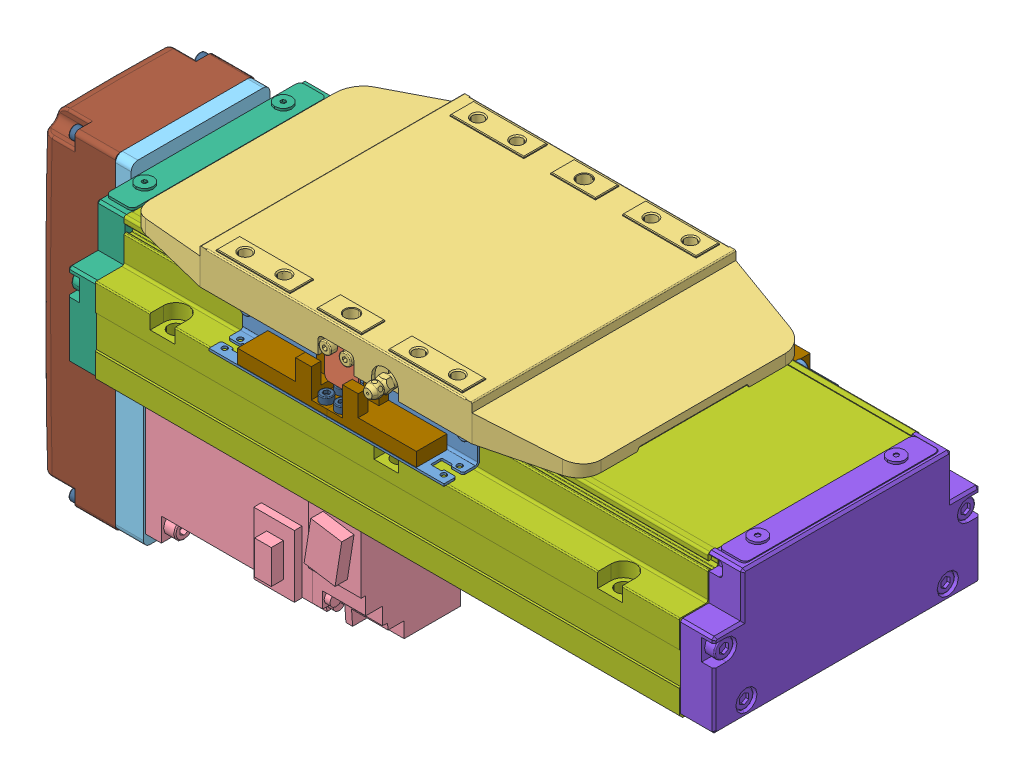
SolidWorks assembly G12-BM-400W, configuration Default. Lengths in mm.
Overall size (330.51 158.5 133.6).
25 component instances, 11 part files, 62 mates.
Components (placement in the parent):
- 304开关座片G5-12^G12-BM-400W-1: 304开关座片G5-12^G12-BM-400W [Default] at (209 38.5 -47.2) x (-1 0 0) z (0 0 -1) size (52.5 15.7 21) (virtual)
- 304开关座片G5-12^G12-BM-400W-2: 304开关座片G5-12^G12-BM-400W [Default] at (54 38.5 47.2) size (52.5 15.7 21) (virtual)
- 304开关座片G5-12^G12-BM-400W-3: 304开关座片G5-12^G12-BM-400W [Default] at (106.5 38.5 47.2) size (52.5 15.7 21) (virtual)
- 304感应片G8-12^G12-BM-400W-1: 304感应片G8-12^G12-BM-400W [Default] at (106.5 56.7 0) x (1 0 0) z (0 0 -1) size (15 17 1) (virtual)
- 304感应片G8-12^G12-BM-400W-2: 304感应片G8-12^G12-BM-400W [Default] at (106.5 56.7 0) x (-1 0 0) z (0 0 1) size (15 17 1) (virtual)
- 滑台G12^G12-BM-400W-1: 滑台G12^G12-BM-400W [Default] at (106.5 59.3 0) size (201.5 16.7 133.6) (virtual)
- 三菱400W^G12-BM-400W-1: 三菱400W^G12-BM-400W [Default] at (-7.5 -47.5 0) x (0 0 1) z (0 1 0) size (68.8 128.3 60) (virtual)
- 电机板G12-BLR-P60^G12-BM-400W-1: 电机板G12-BLR-P60^G12-BM-400W [Default] at origin size (12.5 146 62) (virtual)
- 丝杆座板G12^G12-BM-400W-1: 丝杆座板G12^G12-BM-400W [Default] at origin size (20.5 58.7 119) (virtual)
- 复件 复件 底座GY12+211^G12-BM-400W-1: 复件 复件 底座GY12+211^G12-BM-400W [默认] x (0 0 -1) z (1 0 0) size (120 58 261) (virtual)
- 塑胶轴承座G12^G12-BM-400W-4: 塑胶轴承座G12^G12-BM-400W [Default] at (261 0 0) size (15 58.9 119) (virtual)
- 复件 复件 光电开关EE-SX674^G12-BM-400W-1: 复件 复件 光电开关EE-SX674^G12-BM-400W [默认] at (66.5 41.8 49.4) size (40 15.5 13.6) (virtual)
- 复件 复件 光电开关EE-SX674^G12-BM-400W-2: 复件 复件 光电开关EE-SX674^G12-BM-400W [默认] at (146.5 41.8 63) x (-1 0 0) z (0 0 -1) size (40 15.5 13.6) (virtual)
- 复件 复件 光电开关EE-SX674^G12-BM-400W-3: 复件 复件 光电开关EE-SX674^G12-BM-400W [默认] at (196.5 41.8 -49.4) x (-1 0 0) z (0 0 -1) size (40 15.5 13.6) (virtual)
- hexagon socket head cap screws gb-5: hexagon socket head cap screws gb [GB_FASTENER_SCREWS_HSHCS M3X5-N] at (103 47.4 52.7) x (0 -1 0) z (0 0 1) size (8 5.5 5.5)
- hexagon socket head cap screws gb-6: hexagon socket head cap screws gb [GB_FASTENER_SCREWS_HSHCS M3X5-N] at (103 47.4 59.7) x (0 -1 0) z (0.994193 0 0.107614) size (8 5.5 5.5)
- hexagon socket head cap screws gb-7: hexagon socket head cap screws gb [GB_FASTENER_SCREWS_HSHCS M3X5-N] at (110 47.4 59.7) x (0 -1 0) z (0.983929 0 -0.178562) size (8 5.5 5.5)
- hexagon socket head cap screws gb-8: hexagon socket head cap screws gb [GB_FASTENER_SCREWS_HSHCS M3X5-N] at (110 47.4 52.7) x (0 -1 0) z (0 0 1) size (8 5.5 5.5)
- hexagon socket head cap screws gb-9: hexagon socket head cap screws gb [GB_FASTENER_SCREWS_HSHCS M3X20-N] at (-41.2 60.5 -28) size (23 5.5 5.5)
- hexagon socket head cap screws gb-10: hexagon socket head cap screws gb [GB_FASTENER_SCREWS_HSHCS M3X20-N] at (-41.2 60.5 28) x (1 0 0) z (0 -0.477409 0.878681) size (23 5.5 5.5)
- hexagon socket head cap screws gb-11: hexagon socket head cap screws gb [GB_FASTENER_SCREWS_HSHCS M3X20-N] at (-41.2 -79.5 28) size (23 5.5 5.5)
- hexagon socket head cap screws gb-12: hexagon socket head cap screws gb [GB_FASTENER_SCREWS_HSHCS M3X20-N] at (-41.2 -79.5 -28) size (23 5.5 5.5)
- hexagon socket head cap screws gb-13: hexagon socket head cap screws gb [GB_FASTENER_SCREWS_HSHCS M3X5-N] at (160 47.4 -59.7) x (0 -1 0) z (0 0 1) size (8 5.5 5.5)
- hexagon socket head cap screws gb-14: hexagon socket head cap screws gb [GB_FASTENER_SCREWS_HSHCS M3X5-N] at (160 47.4 -52.7) x (0 -1 0) z (0 0 1) size (8 5.5 5.5)
- 复件 同步轮罩壳G8^G12-BM-400W-1: 复件 同步轮罩壳G8^G12-BM-400W [默认] at (-53 -9.5 0) x (0 1 0) z (0 0 -1) size (146 34.51 62.01) (virtual)
Mates (geometry in assembly coordinates):
- 宽度3: width: plane of 丝杆座板G12^G12-BM-400W-1 through (-13 37.5 59.5) normal (0 0 1); plane of 丝杆座板G12^G12-BM-400W-1 through (-13 2 -59.5) normal (0 0 -1); plane of 复件 复件 底座GY12+211^G12-BM-400W-1 through (261 12.5 -59.5) normal (0 0 -1); plane of 复件 复件 底座GY12+211^G12-BM-400W-1 through (261 26.5 59.5) normal (0 0 1)
- 距离2: distance = 1 mm: plane of 复件 复件 底座GY12+211^G12-BM-400W-1 through (261 0 58.5) normal (0 -1 0); plane of 丝杆座板G12^G12-BM-400W-1 through (-13 1 58.5) normal (0 -1 0)
- 宽度4: width: plane of 电机板G12-BLR-P60^G12-BM-400W-1 through (-59.5 -79.5 -31) normal (0 0 -1); plane of 电机板G12-BLR-P60^G12-BM-400W-1 through (-59.5 60.5 31) normal (0 0 1); plane of 丝杆座板G12^G12-BM-400W-1 through (-13 2 -59.5) normal (0 0 -1); plane of 丝杆座板G12^G12-BM-400W-1 through (-13 37.5 59.5) normal (0 0 1)
- 距离3: distance = 4.8 mm: plane of 电机板G12-BLR-P60^G12-BM-400W-1 through (-59.5 63.5 -28) normal (0 1 0); plane of 丝杆座板G12^G12-BM-400W-1 through (-10 58.7 41.5) normal (0 1 0)
- 重合11: coincident: plane of 丝杆座板G12^G12-BM-400W-1 through (0 0 0) normal (1 0 0); plane of 复件 复件 底座GY12+211^G12-BM-400W-1 through (0 57 46.2) normal (-1 0 0)
- 重合12: coincident: plane of 电机板G12-BLR-P60^G12-BM-400W-1 through (-13 60.5 28) normal (1 0 0); plane of 丝杆座板G12^G12-BM-400W-1 through (-13 0 0) normal (-1 0 0)
- 宽度7: width: plane of 电机板G12-BLR-P60^G12-BM-400W-1 through (-59.5 -79.5 -31) normal (0 0 -1); plane of 电机板G12-BLR-P60^G12-BM-400W-1 through (-59.5 60.5 31) normal (0 0 1); plane of 三菱400W^G12-BM-400W-1 through (67 -17.5 30) normal (0 0 1); plane of 三菱400W^G12-BM-400W-1 through (67 -77.5 -30) normal (0 0 -1)
- 距离4: distance = 5 mm: plane of 三菱400W^G12-BM-400W-1 through (67 -77.5 30) normal (0 -1 0); plane of 电机板G12-BLR-P60^G12-BM-400W-1 through (-59.5 -82.5 28) normal (0 -1 0)
- 重合14: coincident: plane of 三菱400W^G12-BM-400W-1 through (-7.5 -47.5 0) normal (-1 0 0); plane of 电机板G12-BLR-P60^G12-BM-400W-1 through (-7.5 -79.5 28) normal (1 0 0)
- 宽度8: width: plane of 滑台G12^G12-BM-400W-1 through (45.75 76 59) normal (0 0 1); plane of 滑台G12^G12-BM-400W-1 through (167.25 76 -59) normal (0 0 -1); plane of 复件 复件 底座GY12+211^G12-BM-400W-1 through (261 12.5 -59.5) normal (0 0 -1); plane of 复件 复件 底座GY12+211^G12-BM-400W-1 through (261 26.5 59.5) normal (0 0 1)
- 距离5: distance = 76 mm: plane of 滑台G12^G12-BM-400W-1 through (15.75 76 -41.214) normal (0 1 0); plane of 复件 复件 底座GY12+211^G12-BM-400W-1 through (261 0 58.5) normal (0 -1 0)
- 宽度9: width: plane of 304感应片G8-12^G12-BM-400W-2 through (99 64 56.5) normal (-1 0 0); plane of 304感应片G8-12^G12-BM-400W-2 through (114 51 56.5) normal (1 0 0); plane of 滑台G12^G12-BM-400W-1 through (98.5 65 55.5) normal (1 0 0); plane of 滑台G12^G12-BM-400W-1 through (114.5 59.3 55.5) normal (-1 0 0)
- 距离6: distance = 10.3 mm: plane of 304感应片G8-12^G12-BM-400W-2 through (101 49 56.5) normal (0 -1 0); plane of 滑台G12^G12-BM-400W-1 through (15.75 59.3 -41.214) normal (0 -1 0)
- 距离7: distance = 2.5 mm: plane of 304感应片G8-12^G12-BM-400W-2 through (112 51 56.5) normal (0 0 1); plane of 滑台G12^G12-BM-400W-1 through (45.75 76 59) normal (0 0 1)
- 宽度10: width: plane of 304感应片G8-12^G12-BM-400W-1 through (99 51 -56.5) normal (-1 0 0); plane of 304感应片G8-12^G12-BM-400W-1 through (114 64 -56.5) normal (1 0 0); plane of 滑台G12^G12-BM-400W-1 through (98.5 65 -55.5) normal (1 0 0); plane of 滑台G12^G12-BM-400W-1 through (114.5 59.3 -55.5) normal (-1 0 0)
- 距离8: distance = 2.5 mm: plane of 304感应片G8-12^G12-BM-400W-1 through (101 51 -56.5) normal (0 0 -1); plane of 滑台G12^G12-BM-400W-1 through (167.25 76 -59) normal (0 0 -1)
- 距离9: distance = 10.3 mm: plane of 304感应片G8-12^G12-BM-400W-1 through (112 49 -56.5) normal (0 -1 0); plane of 滑台G12^G12-BM-400W-1 through (15.75 59.3 -41.214) normal (0 -1 0)
- 宽度14: width: plane of 塑胶轴承座G12^G12-BM-400W-4 through (276 37.5 59.5) normal (0 0 1); plane of 塑胶轴承座G12^G12-BM-400W-4 through (276 2 -59.5) normal (0 0 -1); plane of 复件 复件 底座GY12+211^G12-BM-400W-1 through (261 12.5 -59.5) normal (0 0 -1); plane of 复件 复件 底座GY12+211^G12-BM-400W-1 through (261 26.5 59.5) normal (0 0 1)
- 重合23: coincident: plane of 复件 复件 底座GY12+211^G12-BM-400W-1 through (261 57 46.2) normal (1 0 0); plane of 塑胶轴承座G12^G12-BM-400W-4 through (261 0 0) normal (-1 0 0)
- 距离10: distance = 1 mm: plane of 塑胶轴承座G12^G12-BM-400W-4 through (276 1 58.5) normal (0 -1 0); plane of 复件 复件 底座GY12+211^G12-BM-400W-1 through (261 0 58.5) normal (0 -1 0)
- 距离11: distance = 67 mm: plane of 304开关座片G5-12^G12-BM-400W-2 through (54 42.8 49.2) normal (-1 0 0); plane of 丝杆座板G12^G12-BM-400W-1 through (-13 0 0) normal (-1 0 0)
- 距离12: distance = 105 mm: plane of 304开关座片G5-12^G12-BM-400W-3 through (159 42.8 49.2) normal (1 0 0); plane of 304开关座片G5-12^G12-BM-400W-2 through (54 42.8 49.2) normal (-1 0 0)
- 宽度15: width: plane of 复件 复件 底座GY12+211^G12-BM-400W-1 through (261 51.25 46.2) normal (0 1 0); plane of 复件 复件 底座GY12+211^G12-BM-400W-1 through (261 54.75 46.7) normal (0 -1 0); cylinder of 304开关座片G5-12^G12-BM-400W-2 through (58 53 42.2) axis (0 0 -1) radius 2.75
- 重合28: coincident: plane of 304开关座片G5-12^G12-BM-400W-2 through (106.5 40.8 63.2) normal (0 -1 0); plane of 304开关座片G5-12^G12-BM-400W-3 through (159 40.8 63.2) normal (0 -1 0)
- 重合29: coincident: plane of 304开关座片G5-12^G12-BM-400W-2 through (106.5 56.5 48.2) normal (0 0 1); plane of 304开关座片G5-12^G12-BM-400W-3 through (159 56.5 48.2) normal (0 0 1)
- 重合30: coincident: plane of 304开关座片G5-12^G12-BM-400W-2 through (106.5 42.8 47.2) normal (0 0 -1); plane of 复件 复件 底座GY12+211^G12-BM-400W-1 through (261 50.75 47.2) normal (0 0 1)
- 宽度16: width: plane of 复件 复件 底座GY12+211^G12-BM-400W-1 through (261 51.25 -46.7) normal (0 1 0); plane of 复件 复件 底座GY12+211^G12-BM-400W-1 through (261 54.75 -46.2) normal (0 -1 0); cylinder of 304开关座片G5-12^G12-BM-400W-1 through (205 53 -42.2) axis (0 0 1) radius 2.75
- 重合36: coincident: plane of 304开关座片G5-12^G12-BM-400W-1 through (156.5 42.8 -47.2) normal (0 0 1); plane of 复件 复件 底座GY12+211^G12-BM-400W-1 through (261 40 -47.2) normal (0 0 -1)
- 宽度17: width: plane of 304开关座片G5-12^G12-BM-400W-2 through (54 42.8 49.2) normal (-1 0 0); plane of 304开关座片G5-12^G12-BM-400W-3 through (159 42.8 49.2) normal (1 0 0); plane of 304感应片G8-12^G12-BM-400W-2 through (99 64 56.5) normal (-1 0 0); plane of 304感应片G8-12^G12-BM-400W-2 through (114 51 56.5) normal (1 0 0)
- 距离14: distance = 67 mm: plane of 304开关座片G5-12^G12-BM-400W-1 through (209 42.8 -49.2) normal (1 0 0); plane of 塑胶轴承座G12^G12-BM-400W-4 through (276 0 0) normal (1 0 0)
- 重合37: coincident: plane of 304开关座片G5-12^G12-BM-400W-2 through (106.5 41.8 49.2) normal (0 1 0); plane of 复件 复件 光电开关EE-SX674^G12-BM-400W-1 through (106.5 41.8 63) normal (0 -1 0)
- 同心7: concentric: cylinder of 304开关座片G5-12^G12-BM-400W-2 through (103 43.5 59.7) axis (0 -1 0) radius 1.23; cylinder of 复件 复件 光电开关EE-SX674^G12-BM-400W-1 through (103 30.8 59.7) axis (0 1 0) radius 1.75
- 同心8: concentric: cylinder of 304开关座片G5-12^G12-BM-400W-2 through (103 43.5 52.7) axis (0 -1 0) radius 1.23; cylinder of 复件 复件 光电开关EE-SX674^G12-BM-400W-1 through (103 30.8 52.7) axis (0 1 0) radius 1.75
- 重合38: coincident: plane of 304开关座片G5-12^G12-BM-400W-3 through (159 41.8 49.2) normal (0 1 0); plane of 复件 复件 光电开关EE-SX674^G12-BM-400W-2 through (106.5 41.8 49.4) normal (0 -1 0)
- 同心9: concentric: cylinder of 304开关座片G5-12^G12-BM-400W-3 through (110 43.5 59.7) axis (0 -1 0) radius 1.23; cylinder of 复件 复件 光电开关EE-SX674^G12-BM-400W-2 through (110 30.8 59.7) axis (0 1 0) radius 1.75
- 同心10: concentric: cylinder of 304开关座片G5-12^G12-BM-400W-3 through (110 43.5 52.7) axis (0 -1 0) radius 1.23; cylinder of 复件 复件 光电开关EE-SX674^G12-BM-400W-2 through (110 30.8 52.7) axis (0 1 0) radius 1.75
- 同心11: concentric: cylinder of 304开关座片G5-12^G12-BM-400W-1 through (160 43.5 -52.7) axis (0 -1 0) radius 1.23; cylinder of 复件 复件 光电开关EE-SX674^G12-BM-400W-3 through (160 30.8 -52.7) axis (0 1 0) radius 1.75
- 重合39: coincident: plane of 304开关座片G5-12^G12-BM-400W-1 through (156.5 41.8 -49.2) normal (0 1 0); plane of 复件 复件 光电开关EE-SX674^G12-BM-400W-3 through (156.5 41.8 -63) normal (0 -1 0)
- 同心12: concentric: cylinder of 304开关座片G5-12^G12-BM-400W-1 through (160 43.5 -59.7) axis (0 -1 0) radius 1.23; cylinder of 复件 复件 光电开关EE-SX674^G12-BM-400W-3 through (160 30.8 -59.7) axis (0 1 0) radius 1.75
- 重合44: coincident: plane of 复件 复件 光电开关EE-SX674^G12-BM-400W-1 through (99.5 44.4 63) normal (0 1 0); plane of hexagon socket head cap screws gb-5 through (103 44.4 52.7) normal (0 -1 0)
- 同心17: concentric: cylinder of 复件 复件 光电开关EE-SX674^G12-BM-400W-1 through (103 30.8 52.7) axis (0 1 0) radius 1.75; cylinder of hexagon socket head cap screws gb-5 through (103 39.4 52.7) axis (0 1 0) radius 1.5
- 重合45: coincident: plane of 复件 复件 光电开关EE-SX674^G12-BM-400W-1 through (99.5 44.4 63) normal (0 1 0); plane of hexagon socket head cap screws gb-6 through (103 44.4 59.7) normal (0 -1 0)
- 同心18: concentric: cylinder of 复件 复件 光电开关EE-SX674^G12-BM-400W-1 through (103 30.8 59.7) axis (0 1 0) radius 1.75; cylinder of hexagon socket head cap screws gb-6 through (103 39.4 59.7) axis (0 1 0) radius 1.5
- 同心19: concentric: cylinder of 复件 复件 光电开关EE-SX674^G12-BM-400W-2 through (110 30.8 59.7) axis (0 1 0) radius 1.75; cylinder of hexagon socket head cap screws gb-7 through (110 39.4 59.7) axis (0 1 0) radius 1.5
- 重合46: coincident: plane of 复件 复件 光电开关EE-SX674^G12-BM-400W-2 through (113.5 44.4 49.4) normal (0 1 0); plane of hexagon socket head cap screws gb-7 through (110 44.4 59.7) normal (0 -1 0)
- 同心20: concentric: cylinder of 复件 复件 光电开关EE-SX674^G12-BM-400W-2 through (110 30.8 52.7) axis (0 1 0) radius 1.75; cylinder of hexagon socket head cap screws gb-8 through (110 39.4 52.7) axis (0 1 0) radius 1.5
- 重合47: coincident: plane of 复件 复件 光电开关EE-SX674^G12-BM-400W-2 through (113.5 44.4 49.4) normal (0 1 0); plane of hexagon socket head cap screws gb-8 through (110 44.4 52.7) normal (0 -1 0)
- 同心242: concentric: cylinder of 复件 复件 光电开关EE-SX674^G12-BM-400W-3 through (160 30.8 -59.7) axis (0 1 0) radius 1.75; cylinder of hexagon socket head cap screws gb-13 through (160 39.4 -59.7) axis (0 1 0) radius 1.5
- 重合512: coincident: plane of 复件 复件 光电开关EE-SX674^G12-BM-400W-3 through (163.5 44.4 -63) normal (0 1 0); plane of hexagon socket head cap screws gb-13 through (160 44.4 -59.7) normal (0 -1 0)
- 重合513: coincident: plane of 复件 复件 光电开关EE-SX674^G12-BM-400W-3 through (163.5 44.4 -63) normal (0 1 0); plane of hexagon socket head cap screws gb-14 through (160 44.4 -52.7) normal (0 -1 0)
- 同心243: concentric: cylinder of 复件 复件 光电开关EE-SX674^G12-BM-400W-3 through (160 30.8 -52.7) axis (0 1 0) radius 1.75; cylinder of hexagon socket head cap screws gb-14 through (160 44.4 -52.7) axis (0 1 0) radius 2.75
- 重合516: coincident: plane of 电机板G12-BLR-P60^G12-BM-400W-1 through (-20 -100 200) normal (-1 0 0); plane of 复件 同步轮罩壳G8^G12-BM-400W-1 through (-20 -9.5 0) normal (1 0 0)
- 宽度20: width: plane of 电机板G12-BLR-P60^G12-BM-400W-1 through (-59.5 63.5 -28) normal (0 1 0); plane of 电机板G12-BLR-P60^G12-BM-400W-1 through (-59.5 -82.5 28) normal (0 -1 0); plane of 复件 同步轮罩壳G8^G12-BM-400W-1 through (-20 63.5 -31) normal (0 1 0); plane of 复件 同步轮罩壳G8^G12-BM-400W-1 through (-20 -82.5 -31) normal (0 -1 0)
- 对称1: symmetric: plane of 电机板G12-BLR-P60^G12-BM-400W-1 through (-59.5 -79.5 -31) normal (0 0 -1); plane of 电机板G12-BLR-P60^G12-BM-400W-1 through (-59.5 60.5 31) normal (0 0 1); plane of 复件 同步轮罩壳G8^G12-BM-400W-1 through (-53 -9.5 0) normal (0 0 -1)
- 同心244: concentric: cylinder of hexagon socket head cap screws gb-9 through (-38.2 60.5 -28) axis (-1 0 0) radius 2.75; cylinder of 复件 同步轮罩壳G8^G12-BM-400W-1 through (-54.2 60.5 -28) axis (-1 0 0) radius 1.7
- 重合517: coincident: circle of hexagon socket head cap screws gb-9; plane of 复件 同步轮罩壳G8^G12-BM-400W-1 through (-38.2 62.2 -28) normal (-1 0 0)
- 同心245: concentric: cylinder of hexagon socket head cap screws gb-10 through (-38.2 60.5 28) axis (-1 0 0) radius 2.75; cylinder of 复件 同步轮罩壳G8^G12-BM-400W-1 through (-54.2 60.5 28) axis (-1 0 0) radius 1.7
- 重合518: coincident: circle of hexagon socket head cap screws gb-10; plane of 复件 同步轮罩壳G8^G12-BM-400W-1 through (-38.2 62.2 28) normal (-1 0 0)
- 同心246: concentric: cylinder of hexagon socket head cap screws gb-12 through (-38.2 -79.5 -28) axis (-1 0 0) radius 2.75; cylinder of 复件 同步轮罩壳G8^G12-BM-400W-1 through (-54.2 -79.5 -28) axis (-1 0 0) radius 1.7
- 重合519: coincident: circle of hexagon socket head cap screws gb-12; plane of 复件 同步轮罩壳G8^G12-BM-400W-1 through (-38.2 -77.8 -28) normal (-1 0 0)
- 同心247: concentric: cylinder of hexagon socket head cap screws gb-11 through (-38.2 -79.5 28) axis (-1 0 0) radius 2.75; cylinder of 复件 同步轮罩壳G8^G12-BM-400W-1 through (-54.2 -79.5 28) axis (-1 0 0) radius 1.7
- 重合520: coincident: circle of hexagon socket head cap screws gb-11; plane of 复件 同步轮罩壳G8^G12-BM-400W-1 through (-38.2 -77.8 28) normal (-1 0 0)
